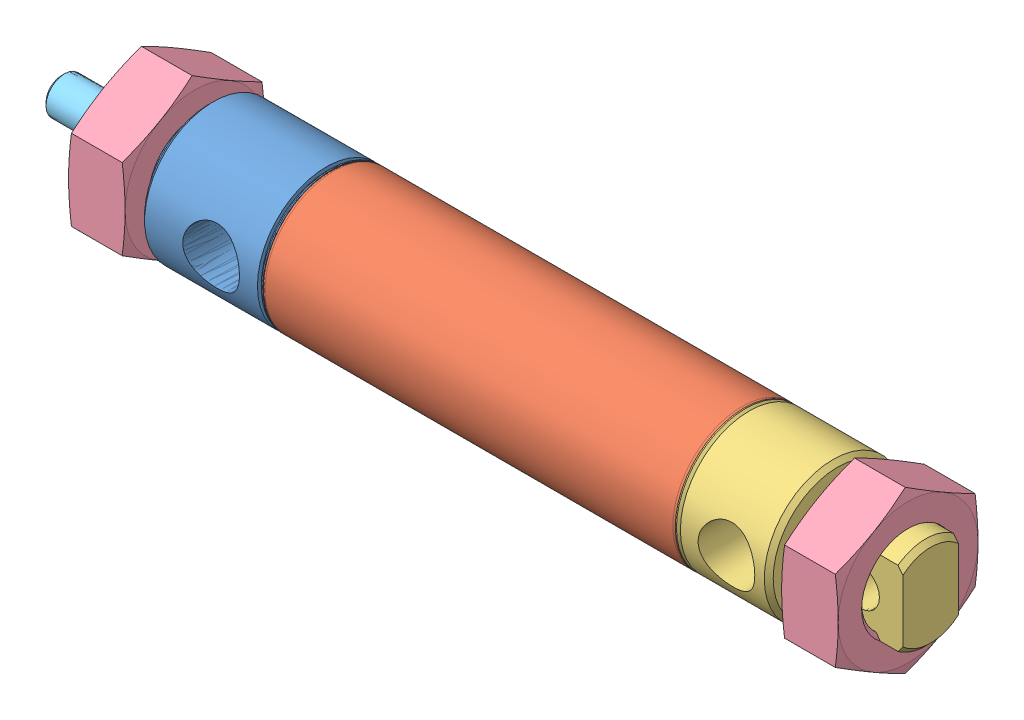
SolidWorks assembly Assem4, configuration Default. Lengths in mm.
Overall size (148.44 27.57 23.88).
7 component instances, 6 part files, 17 mates.
Components (placement in the parent):
- 061_5-DXP0000_0_dummy-1: 061_5-DXP0000_0_dummy [Default] at origin
- 06R000-0_rod_guide-1: 06R000-0_rod_guide [Default] at origin size (38.89 23.52 23.52)
- 06R-2_78350-1: 06R-2_78350 [Default] at (33.2994 0 0) size (72.05 23.52 23.52)
- 06P0000_rear_head-1: 06P0000_rear_head [Default] at (98.3488 0 0) size (37.39 23.52 23.52)
- D-9-1: D-9 [Default] at (122.2375 0 0) x (0 0 -1) z (-1 0 0) size (23.88 27.57 9.65)
- D-9-2: D-9 [Default] at (10.1092 0 0) x (0 0 -1) z (1 0 0) size (23.88 27.57 9.65)
- 061_5-DXP0_rod-1: 061_5-DXP0_rod [Default] at origin size (111.05 22.39 22.39)
Mates (geometry in assembly coordinates):
- Distance2: distance = 0 mm aligned: plane of 06R000-0_rod_guide-1 through (0 0 0) normal (1 0 0); plane of 061_5-DXP0000_0_dummy-1 through (0 0 0) normal (1 0 0)
- Coincident1: coincident aligned: line of 061_5-DXP0000_0_dummy-1 through (80.9 0 0) axis (-1 0 0); line of 06R000-0_rod_guide-1 through (80.9 0 0) axis (-1 0 0)
- Angle3: planar angle = 0 rad aligned: plane of 06R000-0_rod_guide-1 through (0 0 0) normal (0 0 -1); plane of 061_5-DXP0000_0_dummy-1 through (0 0 0) normal (0 0 -1)
- Distance4: distance = 0 mm aligned: plane of 06R-2_78350-1 through (33.2994 0 0) normal (1 0 0); plane of 06R000-0_rod_guide-1 through (33.2994 0 0) normal (1 0 0)
- Coincident2: coincident aligned: line of 06R000-0_rod_guide-1 through (80.9 0 0) axis (-1 0 0); line of 06R-2_78350-1 through (114.1994 0 0) axis (-1 0 0)
- Angle6: planar angle = 0 rad aligned: plane of 06R-2_78350-1 through (33.2994 0 0) normal (0 0 -1); plane of 06R000-0_rod_guide-1 through (0 0 0) normal (0 0 -1)
- Distance6: distance = 0 mm aligned: plane of 06P0000_rear_head-1 through (104.0003 0 0) normal (1 0 0); plane of 06R-2_78350-1 through (104.0003 0 0) normal (1 0 0)
- Coincident3: coincident aligned: line of 06R-2_78350-1 through (114.1994 0 0) axis (-1 0 0); line of 06P0000_rear_head-1 through (179.2488 0 0) axis (-1 0 0)
- Angle9: planar angle = 0 rad aligned: plane of 06P0000_rear_head-1 through (98.3488 0 0) normal (0 0 -1); plane of 06R-2_78350-1 through (33.2994 0 0) normal (0 0 -1)
- Distance7: distance = 0 mm anti-aligned: plane of D-9-1 through (122.2375 0 0) normal (-1 0 0); plane of 06P0000_rear_head-1 through (122.2375 0 0) normal (1 0 0)
- Coincident4: coincident anti-aligned: line of 06P0000_rear_head-1 through (179.2488 0 0) axis (-1 0 0); line of D-9-1 through (41.3375 0 0) axis (1 0 0)
- Angle12: planar angle = 0 rad aligned: plane of D-9-1; plane of 06P0000_rear_head-1 through (98.3488 0 0) normal (0 0 -1)
- Distance9: distance = 0 mm aligned: plane of D-9-2 through (10.1092 0 0) normal (1 0 0); plane of 06R000-0_rod_guide-1 through (10.1092 0 0) normal (1 0 0)
- Coincident5: coincident aligned: line of 06R000-0_rod_guide-1 through (80.9 0 0) axis (-1 0 0); line of D-9-2 through (91.0092 0 0) axis (-1 0 0)
- Angle15: planar angle = 0 rad aligned: plane of D-9-2 through (10.1092 0 0) normal (0 0 -1); plane of 06R000-0_rod_guide-1 through (0 0 0) normal (0 0 -1)
- LimitDistance2: limit distance = 0 mm aligned: plane of 061_5-DXP0_rod-1 through (0 0 0) normal (1 0 0); plane of 06R000-0_rod_guide-1 through (0 0 0) normal (1 0 0)
- Coincident6: coincident aligned: line of 06R000-0_rod_guide-1 through (80.9 0 0) axis (-1 0 0); line of 061_5-DXP0_rod-1 through (80.9 0 0) axis (-1 0 0)
